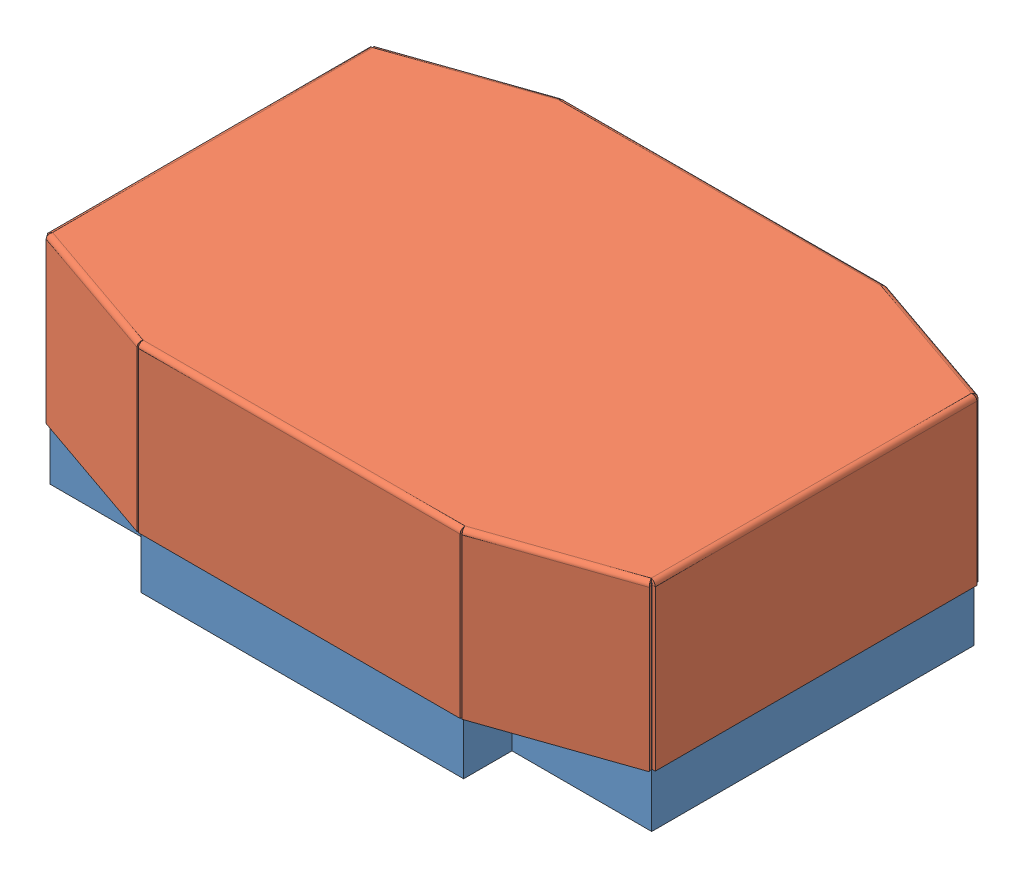
SolidWorks assembly battery, configuration Default. Lengths in mm.
Overall size (287.53 103.12 201.17).
6 component instances, 2 part files, 10 mates.
Components (placement in the parent):
- battery-1: battery [Default] at origin size (152.4 101.6 66.04)
- battery-4: battery [Default] at (0 0 66.04) size (152.4 101.6 66.04)
- battery-5: battery [Default] at (0 0 132.08) size (152.4 101.6 66.04)
- battery-8: battery [Default] at (109.22 0 66.04) x (0 0 -1) z (1 0 0) size (152.4 101.6 66.04)
- battery-9: battery [Default] at (-109.22 0 66.04) x (0 0 1) z (-1 0 0) size (152.4 101.6 66.04)
- battery_tray-1: battery_tray [Default] at (0 101.6 66.04) x (-1 0 0) z (0 1 0) size (287.53 201.17 77.72)
Mates (geometry in assembly coordinates):
- Coincident4: coincident anti-aligned: plane of battery-4 through (0 0 66.04) normal (0 0 1); plane of battery-8 through (109.22 0 66.04) normal (0 0 -1)
- Coincident5: coincident aligned: plane of battery-4 through (-76.2 0 99.06) normal (0 -1 0); plane of battery-8 through (142.24 0 142.24) normal (0 -1 0)
- Coincident6: coincident anti-aligned: plane of battery-4 through (76.2 101.6 33.02) normal (1 0 0); plane of battery-8 through (76.2 101.6 142.24) normal (-1 0 0)
- Coincident7: coincident aligned: plane of battery-5 through (-76.2 0 165.1) normal (0 -1 0); plane of battery-9 through (-142.24 0 -10.16) normal (0 -1 0)
- Coincident8: coincident anti-aligned: plane of battery-4 through (-76.2 101.6 33.02) normal (-1 0 0); plane of battery-9 through (-76.2 101.6 -10.16) normal (1 0 0)
- Coincident9: coincident anti-aligned: plane of battery-8 through (109.22 0 66.04) normal (0 0 -1); plane of battery-9 through (-109.22 0 66.04) normal (0 0 1)
- InPlace1: in place: moOrthogonalPlaneRef_w of battery-4; unknown of battery_tray-1
- Coincident10: coincident aligned: plane of ?; plane of ?
- Coincident11: coincident aligned: moOrthogonalPlaneRef_w of ?; plane of ?
- Coincident12: coincident anti-aligned: 
